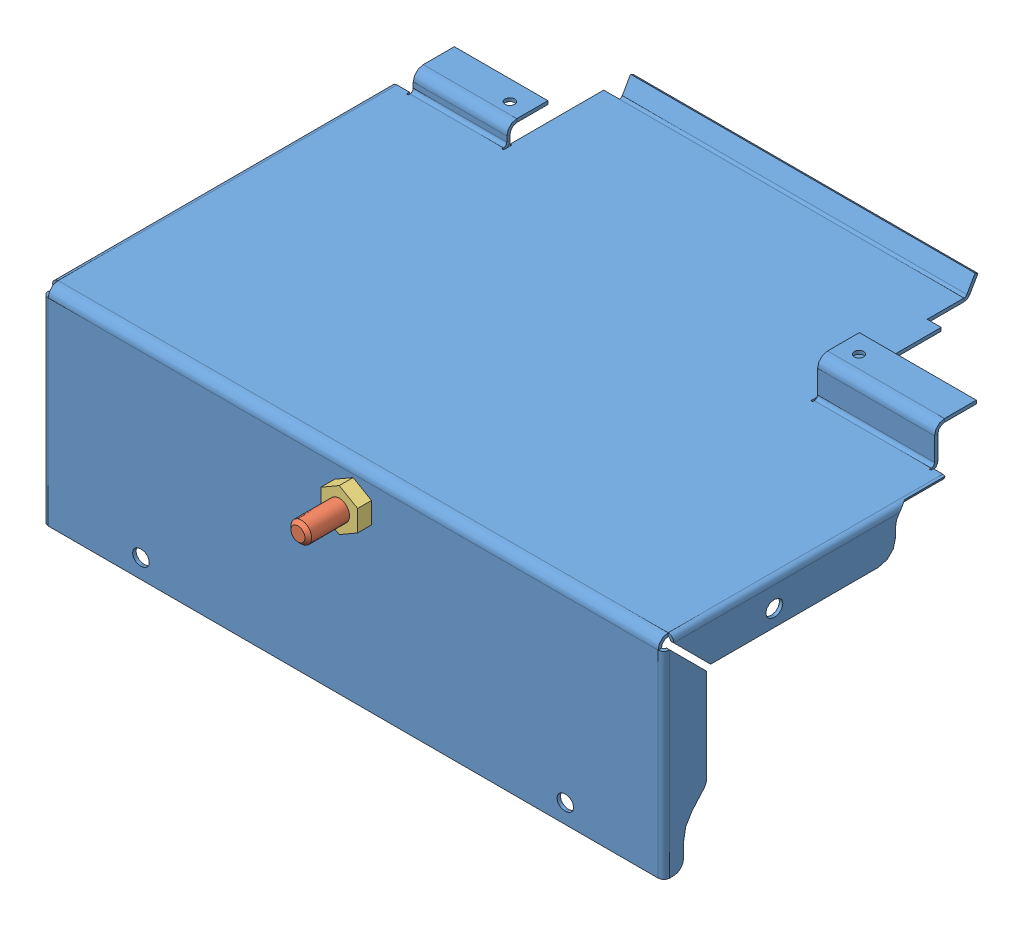
SolidWorks assembly 0003 Radio_top_ASM, configuration Default. Lengths in mm.
Overall size (186 72.99 154.7).
3 component instances, 3 part files, 6 mates.
Components (placement in the parent):
- 0003_1 Radio_top_sheet-1: 0003_1 Radio_top_sheet [Default] at (88.7447 134.3402 188.2995) size (186 72.99 138.2)
- 0003_3 Radio_top_screw-1: 0003_3 Radio_top_screw [Default] at (84.9762 124.0652 192.4027) x (0.009784 0.999952 0) z (0 0 1) size (12.7 11.06 21.65)
- 0003_2 radio_top_nut-1: 0003_2 radio_top_nut [Default] at (84.9762 124.0652 197.5527) x (0.870876 0.491503 0) z (0 0 1) size (12.7 11.06 4.15)
Mates (geometry in assembly coordinates):
- Koncentryczne1: concentric anti-aligned: circle of 0003_1 Radio_top_sheet-1; cylinder of 0003_3 Radio_top_screw-1 through (84.9762 124.0652 214.0527) axis (0 0 -1) radius 3.11
- Wspólnie1: coincident anti-aligned: plane of 0003_1 Radio_top_sheet-1 through (88.7447 134.3402 196.5527) normal (0 0 -1); plane of 0003_3 Radio_top_screw-1 through (84.9762 124.0652 196.5527) normal (0 0 1)
- Koncentryczne2: concentric anti-aligned: cylinder of 0003_3 Radio_top_screw-1 through (84.9762 124.0652 214.0527) axis (0 0 -1) radius 3.11; cylinder of 0003_2 radio_top_nut-1 through (84.9762 124.0652 197.5527) axis (0 0 1) radius 3.11
- Wspólnie3: coincident anti-aligned: plane of 0003_1 Radio_top_sheet-1 through (88.7447 134.3402 197.5527) normal (0 0 1); plane of 0003_2 radio_top_nut-1 through (84.9762 124.0652 197.5527) normal (0 0 -1)
- Równolegle3: parallel anti-aligned: plane of 0003_1 Radio_top_sheet-1 through (-8.0238 134.3402 188.2995) normal (-1 0 0); plane of 0003_3 Radio_top_screw-1 through (90.4762 120.8897 196.5527) normal (1 0 0)
- Równolegle4: parallel aligned: plane of 0003_1 Radio_top_sheet-1 through (177.9762 134.3402 188.2995) normal (1 0 0); plane of 0003_2 radio_top_nut-1 through (90.4762 120.8897 201.7027) normal (1 0 0)
